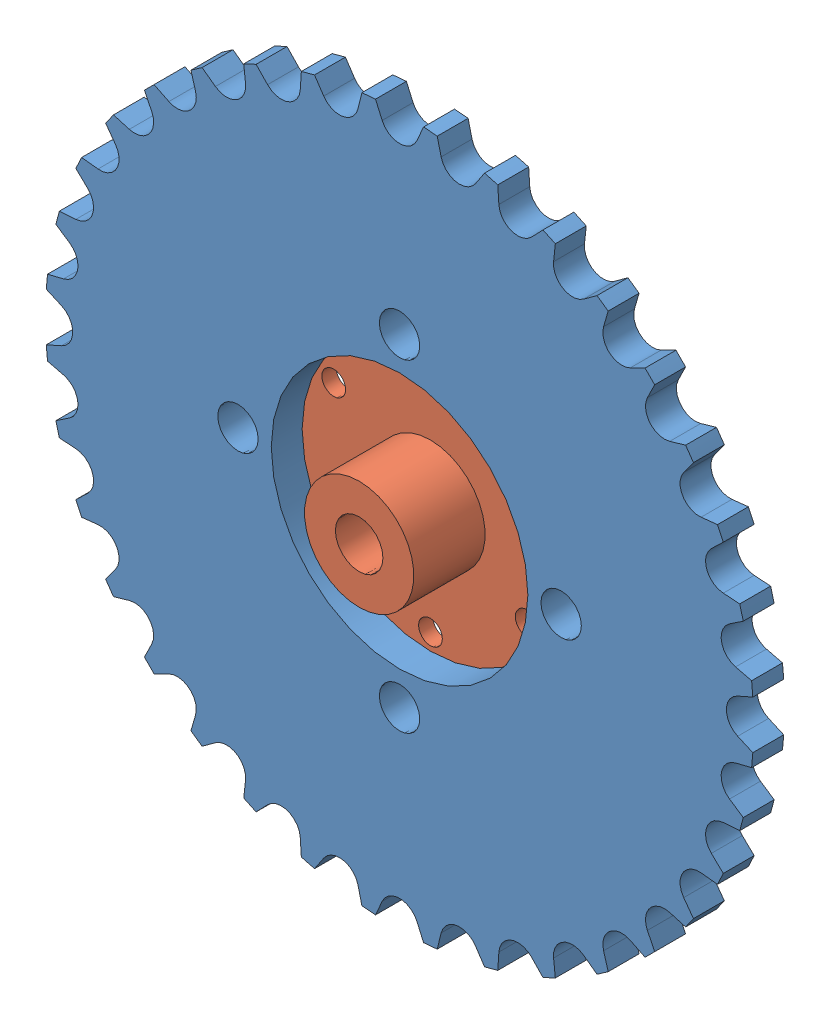
SolidWorks assembly Sprocket, configuration Default. Lengths in mm.
Overall size (148.54 148.54 18).
3 component instances, 3 part files, 5 mates.
Components (placement in the parent):
- 428-36T-1: 428-36T [Default] at (-12.0062 4.4825 -0.3598) size (148.54 148.54 5)
- Hub-Sprocket-1: Hub-Sprocket [Default] at (-12.0062 4.4825 -0.3598) x (1 0 0) z (0 1 0) size (85 7 85)
- Hub10mm-1: Hub10mm [Default] at (-12.0062 4.4825 -3.3598) x (1 0 0) z (0 -1 0) size (55 18 55)
Mates (geometry in assembly coordinates):
- Coincident1: coincident anti-aligned: plane of 428-36T-1 through (-12.0062 4.4825 4.6402) normal (0 0 1); plane of Hub-Sprocket-1 through (-12.0062 4.4825 4.6402) normal (0 0 -1)
- Concentric1: concentric anti-aligned: cylinder of 428-36T-1 through (-12.0062 4.4825 -0.3598) axis (0 0 1) radius 27; cylinder of AlignerSprocket-rev-1 through (-12.0062 4.4825 6.6402) axis (0 0 -1) radius 11.6
- Coincident2: coincident anti-aligned: plane of 428-36T-1 through (-12.0062 4.4825 -0.3598) normal (0 0 -1); plane of Hub10mm-1 through (-12.0062 4.4825 -0.3598) normal (0 0 1)
- Concentric2: concentric anti-aligned: cylinder of AlignerSprocket-1 through (-12.0062 4.4825 6.6402) axis (0 0 -1) radius 11.6; circle of Hub10mm-1
- Coincident3: coincident anti-aligned: cylinder of AlignerSprocket-1 through (8.3454 -7.2675 6.6402) axis (0 0 -1) radius 2.5; circle of Hub10mm-1
